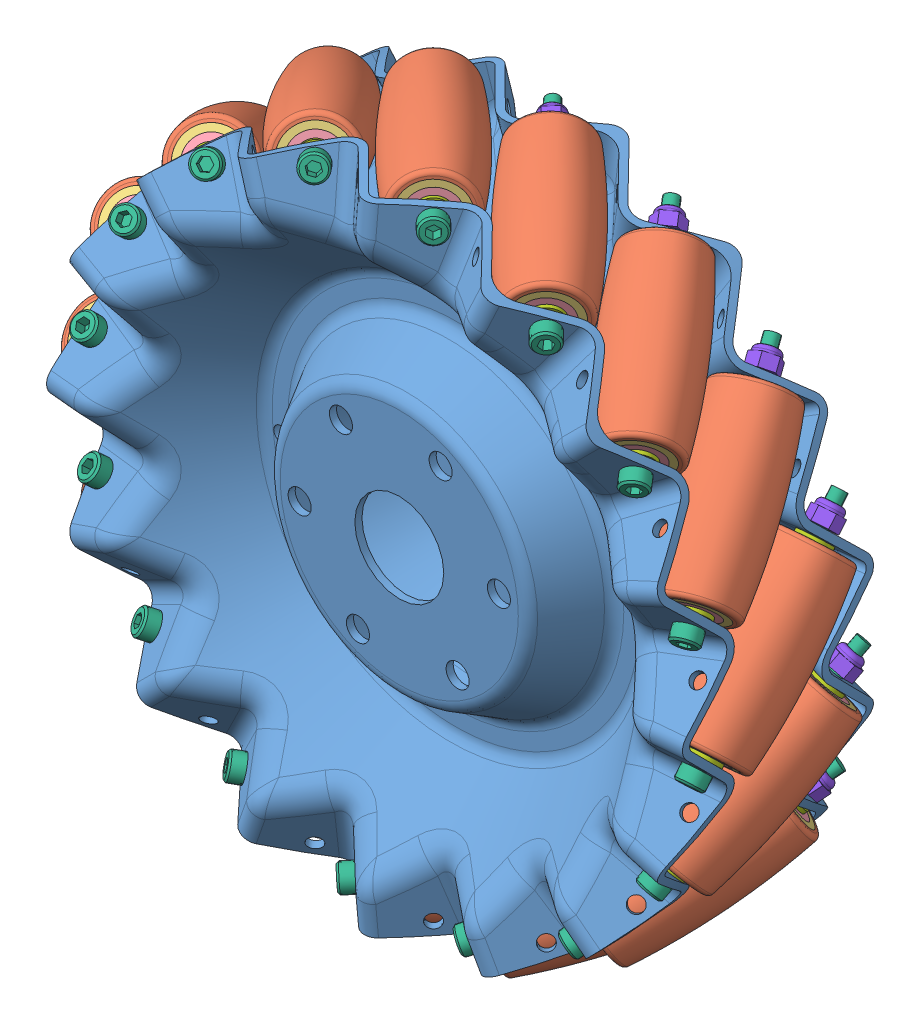
SolidWorks assembly 麦轮组装右, configuration 默认. Lengths in mm.
Overall size (168 168 53.71).
162 component instances, 8 part files, 21 mates.
Components (placement in the parent):
- 麦轮钣金-1: 麦轮钣金 [默认] at (-28.4888 0.9465 132.4522) size (142.88 142.88 24.05)
- 麦轮钣金-3: 麦轮钣金 [默认] at (-28.4888 0.9465 129.2518) x (0.980785 0.19509 0) z (0 0 -1) size (142.88 142.88 24.05)
- 滚花橡胶轮组装-1: 滚花橡胶轮组装 [默认] at (-11.7664 74.8711 111.2311) x (-0.611613 0.360957 0.704017) z (0.544848 -0.453042 0.705615) size (18.5 18.5 53)
  - 滚花橡胶轮外-1: 滚花橡胶轮外 [默认] at (-9.896 1.7835 38.5971) size (18.5 18.5 38)
  - 滚花铝柱-1: 滚花铝柱 [默认] at (-9.896 1.7835 38) x (0.787441 0.61639 0) z (-0.61639 0.787441 0) size (13 38 13)
  - 轴承5X10X4-1: 轴承5X10X4 [默认] at (-9.896 1.7835 55) x (0.442498 0.896769 0) z (-0.896769 0.442498 0) size (10 4 10)
  - 轴承5X10X4-2: 轴承5X10X4 [默认] at (-9.896 1.7835 21) x (0.442498 0.896769 0) z (-0.896769 0.442498 0) size (10 4 10)
  - 铜管3X5-1: 铜管3X5 [默认] at (-9.896 1.7835 38) x (0.823254 0.567673 0) z (-0.567673 0.823254 0) size (5 38 5)
  - 螺丝-1: 螺丝 [默认] at (-9.896 1.7835 59.6) x (-0.462621 0.886556 0) z (0 0 1) size (5.5 5.5 53)
  - 垫片-1: 垫片 [默认] at (-9.896 1.7835 57) x (1 0 0) z (0 -1 0) size (7 0.8 7)
  - 垫片-2: 垫片 [默认] at (-9.896 1.7835 19) x (0.746862 -0.664979 0) z (0.664979 0.746862 0) size (7 0.8 7)
  - 螺母-1: 螺母 [默认] at (-9.896 1.7835 16.2) x (-0.766894 0.641774 0) z (0 0 -1) size (6.35 5.5 4.25)
- 滚花橡胶轮组装-2: 滚花橡胶轮组装 [默认] at (27.0215 56.1049 99.7367) x (0.936151 0.121324 -0.330002) z (0.330002 -0.627061 0.705615) size (18.5 18.5 53)
  - 滚花橡胶轮外-1: 滚花橡胶轮外 [默认] at (-9.896 1.7835 38.5971) size (18.5 18.5 38)
  - 滚花铝柱-1: 滚花铝柱 [默认] at (-9.896 1.7835 38) x (0.787441 0.61639 0) z (-0.61639 0.787441 0) size (13 38 13)
  - 轴承5X10X4-1: 轴承5X10X4 [默认] at (-9.896 1.7835 55) x (0.442498 0.896769 0) z (-0.896769 0.442498 0) size (10 4 10)
  - 轴承5X10X4-2: 轴承5X10X4 [默认] at (-9.896 1.7835 21) x (0.442498 0.896769 0) z (-0.896769 0.442498 0) size (10 4 10)
  - 铜管3X5-1: 铜管3X5 [默认] at (-9.896 1.7835 38) x (0.823254 0.567673 0) z (-0.567673 0.823254 0) size (5 38 5)
  - 螺丝-1: 螺丝 [默认] at (-9.896 1.7835 59.6) x (-0.462621 0.886556 0) z (0 0 1) size (5.5 5.5 53)
  - 垫片-1: 垫片 [默认] at (-9.896 1.7835 57) x (1 0 0) z (0 -1 0) size (7 0.8 7)
  - 垫片-2: 垫片 [默认] at (-9.896 1.7835 19) x (0.746862 -0.664979 0) z (0.664979 0.746862 0) size (7 0.8 7)
  - 螺母-1: 螺母 [默认] at (-9.896 1.7835 16.2) x (-0.766894 0.641774 0) z (0 0 -1) size (6.35 5.5 4.25)
- 滚花橡胶轮组装-3: 滚花橡胶轮组装 [默认] at (40.6784 28.3806 97.7508) x (0.648729 -0.507452 -0.567136) z (0.064917 -0.705615 0.705615) size (18.5 18.5 53)
  - 滚花橡胶轮外-1: 滚花橡胶轮外 [默认] at (-9.896 1.7835 38.5971) size (18.5 18.5 38)
  - 滚花铝柱-1: 滚花铝柱 [默认] at (-9.896 1.7835 38) x (0.787441 0.61639 0) z (-0.61639 0.787441 0) size (13 38 13)
  - 轴承5X10X4-1: 轴承5X10X4 [默认] at (-9.896 1.7835 55) x (0.442498 0.896769 0) z (-0.896769 0.442498 0) size (10 4 10)
  - 轴承5X10X4-2: 轴承5X10X4 [默认] at (-9.896 1.7835 21) x (0.442498 0.896769 0) z (-0.896769 0.442498 0) size (10 4 10)
  - 铜管3X5-1: 铜管3X5 [默认] at (-9.896 1.7835 38) x (0.823254 0.567673 0) z (-0.567673 0.823254 0) size (5 38 5)
  - 螺丝-1: 螺丝 [默认] at (-9.896 1.7835 59.6) x (-0.462621 0.886556 0) z (0 0 1) size (5.5 5.5 53)
  - 垫片-1: 垫片 [默认] at (-9.896 1.7835 57) x (1 0 0) z (0 -1 0) size (7 0.8 7)
  - 垫片-2: 垫片 [默认] at (-9.896 1.7835 19) x (0.746862 -0.664979 0) z (0.664979 0.746862 0) size (7 0.8 7)
  - 螺母-1: 螺母 [默认] at (-9.896 1.7835 16.2) x (-0.766894 0.641774 0) z (0 0 -1) size (6.35 5.5 4.25)
- 滚花橡胶轮组装-4: 滚花橡胶轮组装 [默认] at (53.3201 5.2227 104.8515) x (0.974131 -0.083344 0.210052) z (-0.210052 -0.676746 0.705615) size (18.5 18.5 53)
  - 滚花橡胶轮外-1: 滚花橡胶轮外 [默认] at (-9.896 1.7835 38.5971) size (18.5 18.5 38)
  - 滚花铝柱-1: 滚花铝柱 [默认] at (-9.896 1.7835 38) x (0.787441 0.61639 0) z (-0.61639 0.787441 0) size (13 38 13)
  - 轴承5X10X4-1: 轴承5X10X4 [默认] at (-9.896 1.7835 55) x (0.442498 0.896769 0) z (-0.896769 0.442498 0) size (10 4 10)
  - 轴承5X10X4-2: 轴承5X10X4 [默认] at (-9.896 1.7835 21) x (0.442498 0.896769 0) z (-0.896769 0.442498 0) size (10 4 10)
  - 铜管3X5-1: 铜管3X5 [默认] at (-9.896 1.7835 38) x (0.823254 0.567673 0) z (-0.567673 0.823254 0) size (5 38 5)
  - 螺丝-1: 螺丝 [默认] at (-9.896 1.7835 59.6) x (-0.462621 0.886556 0) z (0 0 1) size (5.5 5.5 53)
  - 垫片-1: 垫片 [默认] at (-9.896 1.7835 57) x (1 0 0) z (0 -1 0) size (7 0.8 7)
  - 垫片-2: 垫片 [默认] at (-9.896 1.7835 19) x (0.746862 -0.664979 0) z (0.664979 0.746862 0) size (7 0.8 7)
  - 螺母-1: 螺母 [默认] at (-9.896 1.7835 16.2) x (-0.766894 0.641774 0) z (0 0 -1) size (6.35 5.5 4.25)
- 滚花橡胶轮组装-6: 滚花橡胶轮组装 [默认] at (49.4638 -23.6017 107.4914) x (0.879664 -0.144722 0.453042) z (-0.453042 -0.544848 0.705615) size (18.5 18.5 53)
  - 滚花橡胶轮外-1: 滚花橡胶轮外 [默认] at (-9.896 1.7835 38.5971) size (18.5 18.5 38)
  - 滚花铝柱-1: 滚花铝柱 [默认] at (-9.896 1.7835 38) x (0.787441 0.61639 0) z (-0.61639 0.787441 0) size (13 38 13)
  - 轴承5X10X4-1: 轴承5X10X4 [默认] at (-9.896 1.7835 55) x (0.442498 0.896769 0) z (-0.896769 0.442498 0) size (10 4 10)
  - 轴承5X10X4-2: 轴承5X10X4 [默认] at (-9.896 1.7835 21) x (0.442498 0.896769 0) z (-0.896769 0.442498 0) size (10 4 10)
  - 铜管3X5-1: 铜管3X5 [默认] at (-9.896 1.7835 38) x (0.823254 0.567673 0) z (-0.567673 0.823254 0) size (5 38 5)
  - 螺丝-1: 螺丝 [默认] at (-9.896 1.7835 59.6) x (-0.462621 0.886556 0) z (0 0 1) size (5.5 5.5 53)
  - 垫片-1: 垫片 [默认] at (-9.896 1.7835 57) x (1 0 0) z (0 -1 0) size (7 0.8 7)
  - 垫片-2: 垫片 [默认] at (-9.896 1.7835 19) x (0.746862 -0.664979 0) z (0.664979 0.746862 0) size (7 0.8 7)
  - 螺母-1: 螺母 [默认] at (-9.896 1.7835 16.2) x (-0.766894 0.641774 0) z (0 0 -1) size (6.35 5.5 4.25)
- 滚花橡胶轮组装-7: 滚花橡胶轮组装 [默认] at (34.7976 -48.3203 109.5966) x (0.769464 -0.121324 0.627061) z (-0.627061 -0.330002 0.705615) size (18.5 18.5 53)
  - 滚花橡胶轮外-1: 滚花橡胶轮外 [默认] at (-9.896 1.7835 38.5971) size (18.5 18.5 38)
  - 滚花铝柱-1: 滚花铝柱 [默认] at (-9.896 1.7835 38) x (0.787441 0.61639 0) z (-0.61639 0.787441 0) size (13 38 13)
  - 轴承5X10X4-1: 轴承5X10X4 [默认] at (-9.896 1.7835 55) x (0.442498 0.896769 0) z (-0.896769 0.442498 0) size (10 4 10)
  - 轴承5X10X4-2: 轴承5X10X4 [默认] at (-9.896 1.7835 21) x (0.442498 0.896769 0) z (-0.896769 0.442498 0) size (10 4 10)
  - 铜管3X5-1: 铜管3X5 [默认] at (-9.896 1.7835 38) x (0.823254 0.567673 0) z (-0.567673 0.823254 0) size (5 38 5)
  - 螺丝-1: 螺丝 [默认] at (-9.896 1.7835 59.6) x (-0.462621 0.886556 0) z (0 0 1) size (5.5 5.5 53)
  - 垫片-1: 垫片 [默认] at (-9.896 1.7835 57) x (1 0 0) z (0 -1 0) size (7 0.8 7)
  - 垫片-2: 垫片 [默认] at (-9.896 1.7835 19) x (0.746862 -0.664979 0) z (0.664979 0.746862 0) size (7 0.8 7)
  - 螺母-1: 螺母 [默认] at (-9.896 1.7835 16.2) x (-0.766894 0.641774 0) z (0 0 -1) size (6.35 5.5 4.25)
- 滚花橡胶轮组装-8: 滚花橡胶轮组装 [默认] at (11.9043 -65.198 110.9878) x (0.708086 -0.026856 0.705615) z (-0.705615 -0.064917 0.705615) size (18.5 18.5 53)
  - 滚花橡胶轮外-1: 滚花橡胶轮外 [默认] at (-9.896 1.7835 38.5971) size (18.5 18.5 38)
  - 滚花铝柱-1: 滚花铝柱 [默认] at (-9.896 1.7835 38) x (0.787441 0.61639 0) z (-0.61639 0.787441 0) size (13 38 13)
  - 轴承5X10X4-1: 轴承5X10X4 [默认] at (-9.896 1.7835 55) x (0.442498 0.896769 0) z (-0.896769 0.442498 0) size (10 4 10)
  - 轴承5X10X4-2: 轴承5X10X4 [默认] at (-9.896 1.7835 21) x (0.442498 0.896769 0) z (-0.896769 0.442498 0) size (10 4 10)
  - 铜管3X5-1: 铜管3X5 [默认] at (-9.896 1.7835 38) x (0.823254 0.567673 0) z (-0.567673 0.823254 0) size (5 38 5)
  - 螺丝-1: 螺丝 [默认] at (-9.896 1.7835 59.6) x (-0.462621 0.886556 0) z (0 0 1) size (5.5 5.5 53)
  - 垫片-1: 垫片 [默认] at (-9.896 1.7835 57) x (1 0 0) z (0 -1 0) size (7 0.8 7)
  - 垫片-2: 垫片 [默认] at (-9.896 1.7835 19) x (0.746862 -0.664979 0) z (0.664979 0.746862 0) size (7 0.8 7)
  - 螺母-1: 螺母 [默认] at (-9.896 1.7835 16.2) x (-0.766894 0.641774 0) z (0 0 -1) size (6.35 5.5 4.25)
- 滚花橡胶轮组装-9: 滚花橡胶轮组装 [默认] at (-20.4065 -80.021 108.2514) x (0.291286 -0.803832 0.518658) z (-0.676746 0.210052 0.705615) size (18.5 18.5 53)
  - 滚花橡胶轮外-1: 滚花橡胶轮外 [默认] at (-9.896 1.7835 38.5971) size (18.5 18.5 38)
  - 滚花铝柱-1: 滚花铝柱 [默认] at (-9.896 1.7835 38) x (0.787441 0.61639 0) z (-0.61639 0.787441 0) size (13 38 13)
  - 轴承5X10X4-1: 轴承5X10X4 [默认] at (-9.896 1.7835 55) x (0.442498 0.896769 0) z (-0.896769 0.442498 0) size (10 4 10)
  - 轴承5X10X4-2: 轴承5X10X4 [默认] at (-9.896 1.7835 21) x (0.442498 0.896769 0) z (-0.896769 0.442498 0) size (10 4 10)
  - 铜管3X5-1: 铜管3X5 [默认] at (-9.896 1.7835 38) x (0.823254 0.567673 0) z (-0.567673 0.823254 0) size (5 38 5)
  - 螺丝-1: 螺丝 [默认] at (-9.896 1.7835 59.6) x (-0.462621 0.886556 0) z (0 0 1) size (5.5 5.5 53)
  - 垫片-1: 垫片 [默认] at (-9.896 1.7835 57) x (1 0 0) z (0 -1 0) size (7 0.8 7)
  - 垫片-2: 垫片 [默认] at (-9.896 1.7835 19) x (0.746862 -0.664979 0) z (0.664979 0.746862 0) size (7 0.8 7)
  - 螺母-1: 螺母 [默认] at (-9.896 1.7835 16.2) x (-0.766894 0.641774 0) z (0 0 -1) size (6.35 5.5 4.25)
- 滚花橡胶轮组装-10: 滚花橡胶轮组装 [默认] at (-46.4094 -74.3284 110.8897) x (0.497758 -0.502453 0.70695) z (-0.544848 0.453042 0.705615) size (18.5 18.5 53)
  - 滚花橡胶轮外-1: 滚花橡胶轮外 [默认] at (-9.896 1.7835 38.5971) size (18.5 18.5 38)
  - 滚花铝柱-1: 滚花铝柱 [默认] at (-9.896 1.7835 38) x (0.787441 0.61639 0) z (-0.61639 0.787441 0) size (13 38 13)
  - 轴承5X10X4-1: 轴承5X10X4 [默认] at (-9.896 1.7835 55) x (0.442498 0.896769 0) z (-0.896769 0.442498 0) size (10 4 10)
  - 轴承5X10X4-2: 轴承5X10X4 [默认] at (-9.896 1.7835 21) x (0.442498 0.896769 0) z (-0.896769 0.442498 0) size (10 4 10)
  - 铜管3X5-1: 铜管3X5 [默认] at (-9.896 1.7835 38) x (0.823254 0.567673 0) z (-0.567673 0.823254 0) size (5 38 5)
  - 螺丝-1: 螺丝 [默认] at (-9.896 1.7835 59.6) x (-0.462621 0.886556 0) z (0 0 1) size (5.5 5.5 53)
  - 垫片-1: 垫片 [默认] at (-9.896 1.7835 57) x (1 0 0) z (0 -1 0) size (7 0.8 7)
  - 垫片-2: 垫片 [默认] at (-9.896 1.7835 19) x (0.746862 -0.664979 0) z (0.664979 0.746862 0) size (7 0.8 7)
  - 螺母-1: 螺母 [默认] at (-9.896 1.7835 16.2) x (-0.766894 0.641774 0) z (0 0 -1) size (6.35 5.5 4.25)
- 滚花橡胶轮组装-11: 滚花橡胶轮组装 [默认] at (-73.8517 -61.7406 110.8897) x (0.267588 -0.654689 0.70695) z (-0.330002 0.627061 0.705615) size (18.5 18.5 53)
  - 滚花橡胶轮外-1: 滚花橡胶轮外 [默认] at (-9.896 1.7835 38.5971) size (18.5 18.5 38)
  - 滚花铝柱-1: 滚花铝柱 [默认] at (-9.896 1.7835 38) x (0.787441 0.61639 0) z (-0.61639 0.787441 0) size (13 38 13)
  - 轴承5X10X4-1: 轴承5X10X4 [默认] at (-9.896 1.7835 55) x (0.442498 0.896769 0) z (-0.896769 0.442498 0) size (10 4 10)
  - 轴承5X10X4-2: 轴承5X10X4 [默认] at (-9.896 1.7835 21) x (0.442498 0.896769 0) z (-0.896769 0.442498 0) size (10 4 10)
  - 铜管3X5-1: 铜管3X5 [默认] at (-9.896 1.7835 38) x (0.823254 0.567673 0) z (-0.567673 0.823254 0) size (5 38 5)
  - 螺丝-1: 螺丝 [默认] at (-9.896 1.7835 59.6) x (-0.462621 0.886556 0) z (0 0 1) size (5.5 5.5 53)
  - 垫片-1: 垫片 [默认] at (-9.896 1.7835 57) x (1 0 0) z (0 -1 0) size (7 0.8 7)
  - 垫片-2: 垫片 [默认] at (-9.896 1.7835 19) x (0.746862 -0.664979 0) z (0.664979 0.746862 0) size (7 0.8 7)
  - 螺母-1: 螺母 [默认] at (-9.896 1.7835 16.2) x (-0.766894 0.641774 0) z (0 0 -1) size (6.35 5.5 4.25)
- 滚花橡胶轮组装-12: 滚花橡胶轮组装 [默认] at (-94.388 -39.6091 110.8897) x (-0.00332 -0.707256 0.70695) z (-0.064917 0.705615 0.705615) size (18.5 18.5 53)
  - 滚花橡胶轮外-1: 滚花橡胶轮外 [默认] at (-9.896 1.7835 38.5971) size (18.5 18.5 38)
  - 滚花铝柱-1: 滚花铝柱 [默认] at (-9.896 1.7835 38) x (0.787441 0.61639 0) z (-0.61639 0.787441 0) size (13 38 13)
  - 轴承5X10X4-1: 轴承5X10X4 [默认] at (-9.896 1.7835 55) x (0.442498 0.896769 0) z (-0.896769 0.442498 0) size (10 4 10)
  - 轴承5X10X4-2: 轴承5X10X4 [默认] at (-9.896 1.7835 21) x (0.442498 0.896769 0) z (-0.896769 0.442498 0) size (10 4 10)
  - 铜管3X5-1: 铜管3X5 [默认] at (-9.896 1.7835 38) x (0.823254 0.567673 0) z (-0.567673 0.823254 0) size (5 38 5)
  - 螺丝-1: 螺丝 [默认] at (-9.896 1.7835 59.6) x (-0.462621 0.886556 0) z (0 0 1) size (5.5 5.5 53)
  - 垫片-1: 垫片 [默认] at (-9.896 1.7835 57) x (1 0 0) z (0 -1 0) size (7 0.8 7)
  - 垫片-2: 垫片 [默认] at (-9.896 1.7835 19) x (0.746862 -0.664979 0) z (0.664979 0.746862 0) size (7 0.8 7)
  - 螺母-1: 螺母 [默认] at (-9.896 1.7835 16.2) x (-0.766894 0.641774 0) z (0 0 -1) size (6.35 5.5 4.25)
- 滚花橡胶轮组装-13: 滚花橡胶轮组装 [默认] at (-104.8916 -11.3035 110.8897) x (-0.273722 -0.652148 0.70695) z (0.210052 0.676746 0.705615) size (18.5 18.5 53)
  - 滚花橡胶轮外-1: 滚花橡胶轮外 [默认] at (-9.896 1.7835 38.5971) size (18.5 18.5 38)
  - 滚花铝柱-1: 滚花铝柱 [默认] at (-9.896 1.7835 38) x (0.787441 0.61639 0) z (-0.61639 0.787441 0) size (13 38 13)
  - 轴承5X10X4-1: 轴承5X10X4 [默认] at (-9.896 1.7835 55) x (0.442498 0.896769 0) z (-0.896769 0.442498 0) size (10 4 10)
  - 轴承5X10X4-2: 轴承5X10X4 [默认] at (-9.896 1.7835 21) x (0.442498 0.896769 0) z (-0.896769 0.442498 0) size (10 4 10)
  - 铜管3X5-1: 铜管3X5 [默认] at (-9.896 1.7835 38) x (0.823254 0.567673 0) z (-0.567673 0.823254 0) size (5 38 5)
  - 螺丝-1: 螺丝 [默认] at (-9.896 1.7835 59.6) x (-0.462621 0.886556 0) z (0 0 1) size (5.5 5.5 53)
  - 垫片-1: 垫片 [默认] at (-9.896 1.7835 57) x (1 0 0) z (0 -1 0) size (7 0.8 7)
  - 垫片-2: 垫片 [默认] at (-9.896 1.7835 19) x (0.746862 -0.664979 0) z (0.664979 0.746862 0) size (7 0.8 7)
  - 螺母-1: 螺母 [默认] at (-9.896 1.7835 16.2) x (-0.766894 0.641774 0) z (0 0 -1) size (6.35 5.5 4.25)
- 滚花橡胶轮组装-14: 滚花橡胶轮组装 [默认] at (-103.7637 18.8671 110.8897) x (-0.502453 -0.497758 0.70695) z (0.453042 0.544848 0.705615) size (18.5 18.5 53)
  - 滚花橡胶轮外-1: 滚花橡胶轮外 [默认] at (-9.896 1.7835 38.5971) size (18.5 18.5 38)
  - 滚花铝柱-1: 滚花铝柱 [默认] at (-9.896 1.7835 38) x (0.787441 0.61639 0) z (-0.61639 0.787441 0) size (13 38 13)
  - 轴承5X10X4-1: 轴承5X10X4 [默认] at (-9.896 1.7835 55) x (0.442498 0.896769 0) z (-0.896769 0.442498 0) size (10 4 10)
  - 轴承5X10X4-2: 轴承5X10X4 [默认] at (-9.896 1.7835 21) x (0.442498 0.896769 0) z (-0.896769 0.442498 0) size (10 4 10)
  - 铜管3X5-1: 铜管3X5 [默认] at (-9.896 1.7835 38) x (0.823254 0.567673 0) z (-0.567673 0.823254 0) size (5 38 5)
  - 螺丝-1: 螺丝 [默认] at (-9.896 1.7835 59.6) x (-0.462621 0.886556 0) z (0 0 1) size (5.5 5.5 53)
  - 垫片-1: 垫片 [默认] at (-9.896 1.7835 57) x (1 0 0) z (0 -1 0) size (7 0.8 7)
  - 垫片-2: 垫片 [默认] at (-9.896 1.7835 19) x (0.746862 -0.664979 0) z (0.664979 0.746862 0) size (7 0.8 7)
  - 螺母-1: 螺母 [默认] at (-9.896 1.7835 16.2) x (-0.766894 0.641774 0) z (0 0 -1) size (6.35 5.5 4.25)
- 滚花橡胶轮组装-15: 滚花橡胶轮组装 [默认] at (-91.1758 46.3095 110.8897) x (-0.654689 -0.267588 0.70695) z (0.627061 0.330002 0.705615) size (18.5 18.5 53)
  - 滚花橡胶轮外-1: 滚花橡胶轮外 [默认] at (-9.896 1.7835 38.5971) size (18.5 18.5 38)
  - 滚花铝柱-1: 滚花铝柱 [默认] at (-9.896 1.7835 38) x (0.787441 0.61639 0) z (-0.61639 0.787441 0) size (13 38 13)
  - 轴承5X10X4-1: 轴承5X10X4 [默认] at (-9.896 1.7835 55) x (0.442498 0.896769 0) z (-0.896769 0.442498 0) size (10 4 10)
  - 轴承5X10X4-2: 轴承5X10X4 [默认] at (-9.896 1.7835 21) x (0.442498 0.896769 0) z (-0.896769 0.442498 0) size (10 4 10)
  - 铜管3X5-1: 铜管3X5 [默认] at (-9.896 1.7835 38) x (0.823254 0.567673 0) z (-0.567673 0.823254 0) size (5 38 5)
  - 螺丝-1: 螺丝 [默认] at (-9.896 1.7835 59.6) x (-0.462621 0.886556 0) z (0 0 1) size (5.5 5.5 53)
  - 垫片-1: 垫片 [默认] at (-9.896 1.7835 57) x (1 0 0) z (0 -1 0) size (7 0.8 7)
  - 垫片-2: 垫片 [默认] at (-9.896 1.7835 19) x (0.746862 -0.664979 0) z (0.664979 0.746862 0) size (7 0.8 7)
  - 螺母-1: 螺母 [默认] at (-9.896 1.7835 16.2) x (-0.766894 0.641774 0) z (0 0 -1) size (6.35 5.5 4.25)
- 滚花橡胶轮组装-16: 滚花橡胶轮组装 [默认] at (-69.0443 66.8457 110.8897) x (-0.707256 0.00332 0.70695) z (0.705615 0.064917 0.705615) size (18.5 18.5 53)
  - 滚花橡胶轮外-1: 滚花橡胶轮外 [默认] at (-9.896 1.7835 38.5971) size (18.5 18.5 38)
  - 滚花铝柱-1: 滚花铝柱 [默认] at (-9.896 1.7835 38) x (0.787441 0.61639 0) z (-0.61639 0.787441 0) size (13 38 13)
  - 轴承5X10X4-1: 轴承5X10X4 [默认] at (-9.896 1.7835 55) x (0.442498 0.896769 0) z (-0.896769 0.442498 0) size (10 4 10)
  - 轴承5X10X4-2: 轴承5X10X4 [默认] at (-9.896 1.7835 21) x (0.442498 0.896769 0) z (-0.896769 0.442498 0) size (10 4 10)
  - 铜管3X5-1: 铜管3X5 [默认] at (-9.896 1.7835 38) x (0.823254 0.567673 0) z (-0.567673 0.823254 0) size (5 38 5)
  - 螺丝-1: 螺丝 [默认] at (-9.896 1.7835 59.6) x (-0.462621 0.886556 0) z (0 0 1) size (5.5 5.5 53)
  - 垫片-1: 垫片 [默认] at (-9.896 1.7835 57) x (1 0 0) z (0 -1 0) size (7 0.8 7)
  - 垫片-2: 垫片 [默认] at (-9.896 1.7835 19) x (0.746862 -0.664979 0) z (0.664979 0.746862 0) size (7 0.8 7)
  - 螺母-1: 螺母 [默认] at (-9.896 1.7835 16.2) x (-0.766894 0.641774 0) z (0 0 -1) size (6.35 5.5 4.25)
- 滚花橡胶轮组装-17: 滚花橡胶轮组装 [默认] at (-40.7387 77.3494 110.8897) x (-0.652148 0.273722 0.70695) z (0.676746 -0.210052 0.705615) size (18.5 18.5 53)
  - 滚花橡胶轮外-1: 滚花橡胶轮外 [默认] at (-9.896 1.7835 38.5971) size (18.5 18.5 38)
  - 滚花铝柱-1: 滚花铝柱 [默认] at (-9.896 1.7835 38) x (0.787441 0.61639 0) z (-0.61639 0.787441 0) size (13 38 13)
  - 轴承5X10X4-1: 轴承5X10X4 [默认] at (-9.896 1.7835 55) x (0.442498 0.896769 0) z (-0.896769 0.442498 0) size (10 4 10)
  - 轴承5X10X4-2: 轴承5X10X4 [默认] at (-9.896 1.7835 21) x (0.442498 0.896769 0) z (-0.896769 0.442498 0) size (10 4 10)
  - 铜管3X5-1: 铜管3X5 [默认] at (-9.896 1.7835 38) x (0.823254 0.567673 0) z (-0.567673 0.823254 0) size (5 38 5)
  - 螺丝-1: 螺丝 [默认] at (-9.896 1.7835 59.6) x (-0.462621 0.886556 0) z (0 0 1) size (5.5 5.5 53)
  - 垫片-1: 垫片 [默认] at (-9.896 1.7835 57) x (1 0 0) z (0 -1 0) size (7 0.8 7)
  - 垫片-2: 垫片 [默认] at (-9.896 1.7835 19) x (0.746862 -0.664979 0) z (0.664979 0.746862 0) size (7 0.8 7)
  - 螺母-1: 螺母 [默认] at (-9.896 1.7835 16.2) x (-0.766894 0.641774 0) z (0 0 -1) size (6.35 5.5 4.25)
Mates (geometry in assembly coordinates):
- 同心25: concentric: cylinder of 麦轮钣金-1 through (-67.7985 -2.9252 132.4522) axis (0 0 1) radius 1.6; cylinder of 麦轮钣金-3 through (-67.7985 -2.9252 129.2518) axis (0 0 -1) radius 1.6
- 同心26: concentric: cylinder of 麦轮钣金-1 through (10.821 4.8181 132.4522) axis (0 0 1) radius 1.6; cylinder of 麦轮钣金-3 through (10.821 4.8181 129.2518) axis (0 0 -1) radius 1.6
- 重合21: coincident: plane of 麦轮钣金-1 through (-13.9632 73.9715 130.852) normal (0 0 -1); plane of 麦轮钣金-3 through (0.0042 -67.8416 130.852) normal (0 0 1)
- 同心27: concentric: cylinder of 麦轮钣金-1 through (24.7553 43.6594 144.9053) axis (-0.544848 0.453042 -0.705615) radius 1.6; cylinder of 滚花橡胶轮组装-1/螺丝-1 through (-1.5064 65.496 110.8947) axis (0.544848 -0.453042 0.705615) radius 1.5
- 重合22: coincident: plane of 麦轮钣金-1 through (22.9202 70.2277 163.3806) normal (-0.544848 0.453042 -0.705615); plane of 滚花橡胶轮组装-1/垫片-1 through (24.7553 43.6594 144.9053) normal (0.544848 -0.453042 0.705615)
- 同心28: concentric: cylinder of 麦轮钣金-1 through (37.0479 20.0325 144.9053) axis (-0.330002 0.627061 -0.705615) radius 1.5875; cylinder of 滚花橡胶轮组装-2/螺丝-1 through (21.1418 50.2568 110.8947) axis (0.330002 -0.627061 0.705615) radius 1.5
- 重合23: coincident: plane of 麦轮钣金-1 through (45.5197 45.2807 163.3806) normal (-0.330002 0.627061 -0.705615); plane of 滚花橡胶轮组装-2/垫片-1 through (37.0479 20.0325 144.9053) normal (0.330002 -0.627061 0.705615)
- 同心29: concentric: cylinder of 麦轮钣金-1 through (39.3631 -6.5002 144.9053) axis (-0.064917 0.705615 -0.705615) radius 1.5875; cylinder of 滚花橡胶轮组装-3/螺丝-1 through (36.2341 27.5105 110.8947) axis (0.064917 -0.705615 0.705615) radius 1.5
- 重合24: coincident: plane of 麦轮钣金-1 through (56.8521 13.5841 163.3806) normal (-0.064917 0.705615 -0.705615); plane of 滚花橡胶轮组装-3/垫片-1 through (39.3631 -6.5002 144.9053) normal (0.064917 -0.705615 0.705615)
- 同心30: concentric: cylinder of 麦轮钣金-1 through (31.3485 -31.8991 144.9053) axis (0.210052 0.676746 -0.705615) radius 1.6; cylinder of 滚花橡胶轮组装-4/螺丝-1 through (41.515 0.8553 110.7537) axis (-0.210052 -0.676746 0.705615) radius 1.5
- 重合25: coincident: plane of 麦轮钣金-1 through (54.856 -21.1193 164.5097) normal (-0.210052 -0.676746 0.705615); plane of 滚花橡胶轮组装-4/螺丝-1 through (29.5699 -31.0926 147.4172) normal (0.210052 0.676746 -0.705615)
- 同心31: concentric: cylinder of 麦轮钣金-1 through (14.2242 -52.2976 144.9053) axis (0.453042 0.544848 -0.705615) radius 1.6; cylinder of 滚花橡胶轮组装-6/螺丝-1 through (36.1513 -25.927 110.7537) axis (-0.453042 -0.544848 0.705615) radius 1.5
- 重合26: coincident: plane of 麦轮钣金-1 through (40.0676 -51.3343 164.5097) normal (-0.453042 -0.544848 0.705615); plane of 滚花橡胶轮组装-6/螺丝-1 through (12.0273 -50.9716 146.7865) normal (0.453042 0.544848 -0.705615)
- 同心32: concentric: cylinder of 麦轮钣金-1 through (-9.4028 -64.5902 144.9053) axis (0.627061 0.330002 -0.705615) radius 1.6; cylinder of 滚花橡胶轮组装-7/螺丝-1 through (20.9469 -48.6181 110.7537) axis (-0.627061 -0.330002 0.705615) radius 1.5
- 重合27: coincident: plane of 麦轮钣金-1 through (14.842 -73.5901 164.5097) normal (-0.627061 -0.330002 0.705615); plane of 滚花橡胶轮组装-7/螺丝-1 through (-11.6809 -62.6815 146.0413) normal (0.627061 0.330002 -0.705615)
- 同心33: concentric: cylinder of 麦轮钣金-1 through (-35.9354 -66.9054 144.9053) axis (0.705615 0.064917 -0.705615) radius 1.6; cylinder of 滚花橡胶轮组装-8/螺丝-1 through (-1.9247 -63.7764 110.8947) axis (-0.705615 -0.064917 0.705615) radius 1.5
- 重合28: coincident: plane of 麦轮钣金-1 through (-15.8511 -84.3944 163.3806) normal (0.705615 0.064917 -0.705615); plane of 滚花橡胶轮组装-8/垫片-1 through (-35.9354 -66.9054 144.9053) normal (-0.705615 -0.064917 0.705615)
- 同心34: concentric: cylinder of 麦轮钣金-1 through (-61.3343 -58.8908 144.9053) axis (0.676746 -0.210052 -0.705615) radius 1.6; cylinder of 滚花橡胶轮组装-9/螺丝-1 through (-28.5799 -69.0572 110.7537) axis (-0.676746 0.210052 0.705615) radius 1.5
- 重合29: coincident: plane of 麦轮钣金-1 through (-50.5546 -82.3983 164.5097) normal (-0.676746 0.210052 0.705615); plane of 滚花橡胶轮组装-9/螺丝-1 through (-61.1394 -56.1751 146.5517) normal (0.676746 -0.210052 -0.705615)
- 同心35: concentric: cylinder of 麦轮钣金-1 through (-81.7328 -41.7665 144.9053) axis (0.544848 -0.453042 -0.705615) radius 1.6; cylinder of 滚花橡胶轮组装-10/螺丝-1 through (-55.3622 -63.6936 110.7537) axis (-0.544848 0.453042 0.705615) radius 1.5
- 重合30: coincident: plane of 麦轮钣金-1 through (-80.7696 -67.6098 164.5097) normal (-0.544848 0.453042 0.705615); plane of 滚花橡胶轮组装-10/螺丝-1 through (-81.5927 -38.6069 145.2527) normal (0.544848 -0.453042 -0.705615)
